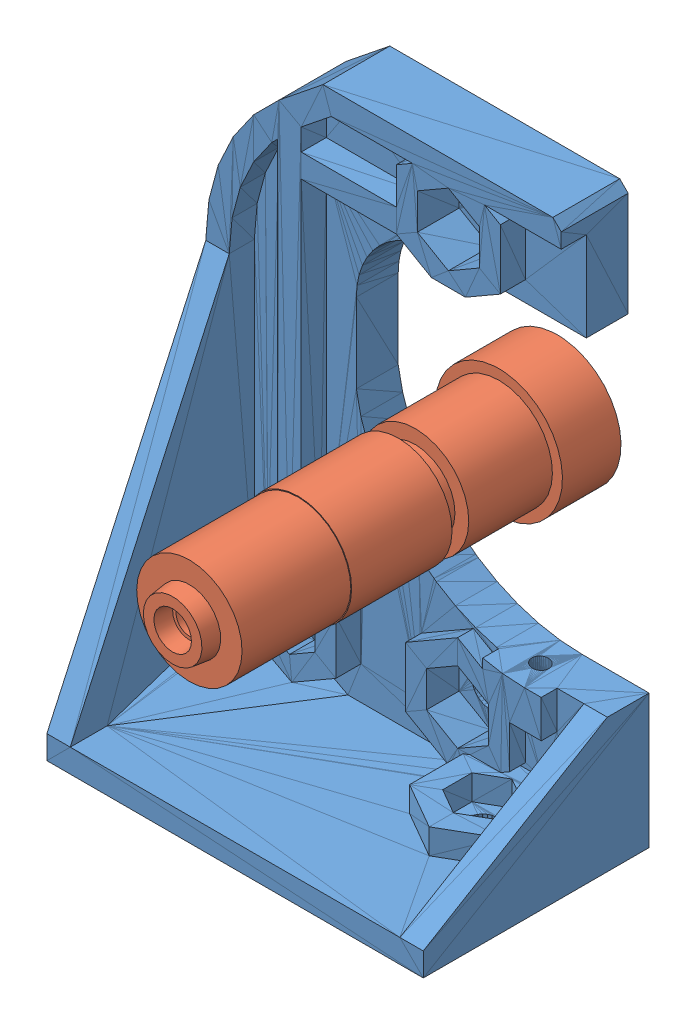
SolidWorks assembly Extruder, configuration Valor predeterminado. Lengths in mm.
Overall size (45 67.49 93).
4 component instances, 4 part files, 3 mates.
Components (placement in the parent):
- extruder-plate-1: extruder-plate [Valor predeterminado] at origin size (45 67.49 27)
- R3DEx5A_base-1: R3DEx5A_base [Valor predeterminado] at (37.8444 65.7677 -29.7499) x (-1 0 -0.000001) z (0 -1 -0.000001) (suppressed, hidden)
- Tito_Extruder_base_v2-1: Tito_Extruder_base_v2 [Valor predeterminado] at (78.1902 5.1133 -4.95) x (0 1 0) z (-1 0 0) (suppressed, hidden)
- Hotend corpo teflon-1: Hotend corpo teflon [Valor predeterminado] at (29.0383 35.0111 2) x (0.999903 -0.013911 0) z (0.013911 0.999903 0) size (15.2 46 15.2)
Mates (geometry in assembly coordinates):
- Coincidente2: coincident anti-aligned: plane of extruder-plate-1 through (17.1 0 0) normal (0.000001 0.000001 -1); plane of R3DEx5A_base-1 through (20.0964 65.7677 0.0001) normal (-0.000001 -0.000001 1)
- Perpendicular1: perpendicular: plane of extruder-plate-1 through (14 67.49 0) normal (0 1 0.000001); plane of R3DEx5A_base-1 through (15.0964 60.7697 -10) normal (-1 0 -0.000001)
- Coincidente8: coincident anti-aligned: plane of extruder-plate-1 through (41.49 67.49 0) normal (0 0 -1); plane of Tito_Extruder_base_v2-1 through (18.0143 5.1433 0) normal (0 0 1)
